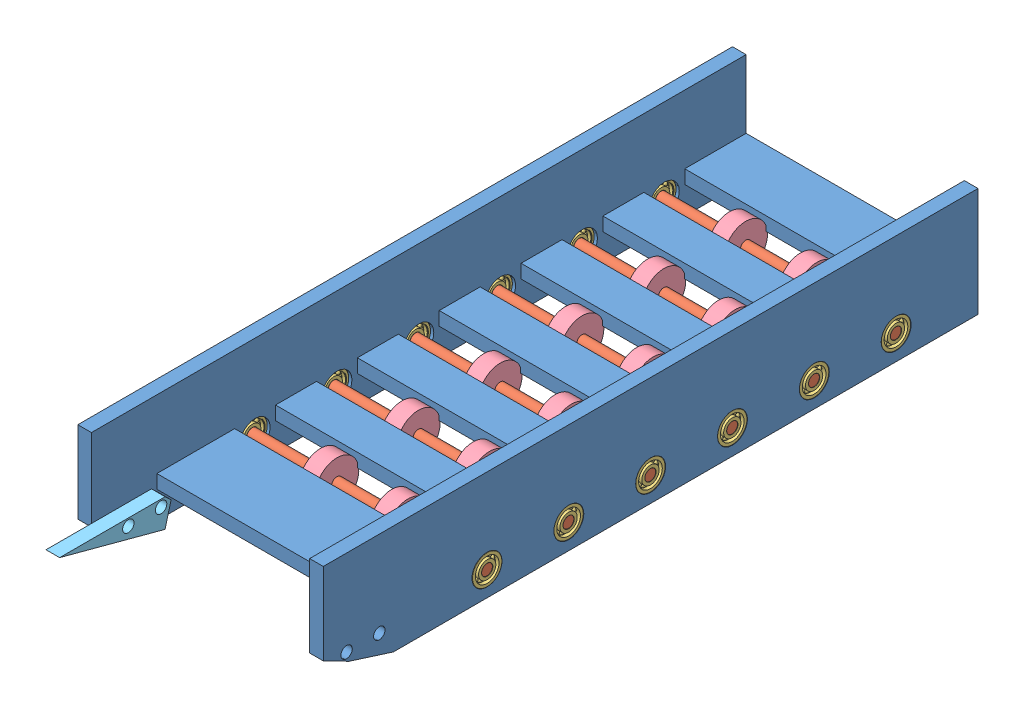
SolidWorks assembly chute_assemble_20241127, configuration 默认. Lengths in mm.
Overall size (90.23 42.03 256.65).
32 component instances, 5 part files, 64 mates.
Components (placement in the parent):
- chute_metal_20241127-1: chute_metal_20241127 [默认] at (2.4605 -4.6428 75) size (90 40 240)
- chute_stick_metal_20241127-1: chute_stick_metal_20241127 [默认] at (47.3105 -10.6428 135) x (0 0 1) z (-1 0 0) size (4 4 90)
- Rolling bearings S719-4 GB 292-94-1: Rolling bearings S719-4 GB 292-94 [Rolling bearings S719-4 GB 292-94] at (-40.6895 -10.6428 135) x (1 0 0) z (0 0.999705 0.024301) size (4 11 11)
- Rolling bearings S719-4 GB 292-94-2: Rolling bearings S719-4 GB 292-94 [Rolling bearings S719-4 GB 292-94] at (45.3905 -10.6428 135) x (-1 0 0) z (0 0.977196 -0.212337) size (4 11 11)
- chute_stickball_metal_20241127-1: chute_stickball_metal_20241127 [默认] at (18.3905 -10.6428 135) x (0 0.978422 0.206615) z (-1 0 0) size (16 16 6)
- chute_stickball_metal_20241127-2: chute_stickball_metal_20241127 [默认] at (-7.6895 -10.6428 135) x (0 -0.199483 0.979901) z (-1 0 0) size (16 16 6)
- Rolling bearings S719-4 GB 292-94-3: Rolling bearings S719-4 GB 292-94 [Rolling bearings S719-4 GB 292-94] at (45.3905 -10.6428 165) x (-1 0 0) z (0 0.977196 -0.212337) size (4 11 11)
- chute_stickball_metal_20241127-3: chute_stickball_metal_20241127 [默认] at (-7.6895 -10.6428 165) x (0 -0.199483 0.979901) z (-1 0 0) size (16 16 6)
- chute_stickball_metal_20241127-4: chute_stickball_metal_20241127 [默认] at (18.3905 -10.6428 165) x (0 0 1) z (-1 0 0) size (16 16 6)
- Rolling bearings S719-4 GB 292-94-4: Rolling bearings S719-4 GB 292-94 [Rolling bearings S719-4 GB 292-94] at (-40.6895 -10.6428 165) x (1 0 0) z (0 0.999705 0.024301) size (4 11 11)
- chute_stick_metal_20241127-2: chute_stick_metal_20241127 [默认] at (47.3105 -10.6428 165) x (0 0 1) z (-1 0 0) size (4 4 90)
- Rolling bearings S719-4 GB 292-94-5: Rolling bearings S719-4 GB 292-94 [Rolling bearings S719-4 GB 292-94] at (45.3905 -10.6428 105) x (-1 0 0) z (0 0.977196 -0.212337) size (4 11 11)
- chute_stickball_metal_20241127-5: chute_stickball_metal_20241127 [默认] at (-7.6895 -10.6428 105) x (0 -0.199483 0.979901) z (-1 0 0) size (16 16 6)
- chute_stickball_metal_20241127-6: chute_stickball_metal_20241127 [默认] at (18.3905 -10.6428 105) x (0 0 1) z (-1 0 0) size (16 16 6)
- Rolling bearings S719-4 GB 292-94-6: Rolling bearings S719-4 GB 292-94 [Rolling bearings S719-4 GB 292-94] at (-40.6895 -10.6428 105) x (1 0 0) z (0 0.999705 0.024301) size (4 11 11)
- chute_stick_metal_20241127-3: chute_stick_metal_20241127 [默认] at (47.3105 -10.6428 105) x (0 0 1) z (-1 0 0) size (4 4 90)
- Rolling bearings S719-4 GB 292-94-7: Rolling bearings S719-4 GB 292-94 [Rolling bearings S719-4 GB 292-94] at (45.3905 -10.6428 195) x (-1 0 0) z (0 0.977196 -0.212337) size (4 11 11)
- chute_stickball_metal_20241127-7: chute_stickball_metal_20241127 [默认] at (-7.6895 -10.6428 195) x (0 -0.199483 0.979901) z (-1 0 0) size (16 16 6)
- chute_stickball_metal_20241127-8: chute_stickball_metal_20241127 [默认] at (18.3905 -10.6428 195) x (0 0.504953 0.863147) z (-1 0 0) size (16 16 6)
- Rolling bearings S719-4 GB 292-94-8: Rolling bearings S719-4 GB 292-94 [Rolling bearings S719-4 GB 292-94] at (-40.6895 -10.6428 195) x (1 0 0) z (0 0.999705 0.024301) size (4 11 11)
- chute_stick_metal_20241127-4: chute_stick_metal_20241127 [默认] at (47.3105 -10.6428 195) x (0 0 1) z (-1 0 0) size (4 4 90)
- chute_stickball_metal_20241127-9: chute_stickball_metal_20241127 [默认] at (-7.6895 -10.6428 225) x (0 -0.092424 0.99572) z (-1 0 0) size (16 16 6)
- chute_stickball_metal_20241127-10: chute_stickball_metal_20241127 [默认] at (18.3905 -10.6428 225) x (0 -0.53296 -0.84614) z (-1 0 0) size (16 16 6)
- Rolling bearings S719-4 GB 292-94-9: Rolling bearings S719-4 GB 292-94 [Rolling bearings S719-4 GB 292-94] at (45.3905 -10.6428 225) x (-1 0 0) z (0 0.977196 -0.212337) size (4 11 11)
- Rolling bearings S719-4 GB 292-94-10: Rolling bearings S719-4 GB 292-94 [Rolling bearings S719-4 GB 292-94] at (-40.6895 -10.6428 225) x (1 0 0) z (0 0.999705 0.024301) size (4 11 11)
- chute_stick_metal_20241127-5: chute_stick_metal_20241127 [默认] at (47.3105 -10.6428 225) x (0 0 1) z (-1 0 0) size (4 4 90)
- Rolling bearings S719-4 GB 292-94-13: Rolling bearings S719-4 GB 292-94 [Rolling bearings S719-4 GB 292-94] at (45.5405 -10.6428 255) x (-1 0 0) z (0 0.977196 -0.212337) size (4 11 11)
- chute_stickball_metal_20241127-13: chute_stickball_metal_20241127 [默认] at (-7.5395 -10.6428 255) x (0 -0.199483 0.979901) z (-1 0 0) size (16 16 6)
- chute_stick_metal_20241127-7: chute_stick_metal_20241127 [默认] at (47.4605 -10.6428 255) x (0 0 1) z (-1 0 0) size (4 4 90)
- Rolling bearings S719-4 GB 292-94-14: Rolling bearings S719-4 GB 292-94 [Rolling bearings S719-4 GB 292-94] at (-40.5395 -10.6428 255) x (1 0 0) z (0 0.999705 0.024301) size (4 11 11)
- chute_stickball_metal_20241127-14: chute_stickball_metal_20241127 [默认] at (18.5405 -10.6428 255) x (0 -0.53296 -0.84614) z (-1 0 0) size (16 16 6)
- chute_intaker_connect_3d_20241128-2: chute_intaker_connect_3d_20241128 [默认] at (-32.5395 -18.8708 293.0176) x (0 0.258819 0.965926) z (-1 0 0) size (40 10.01 5)
Mates (geometry in assembly coordinates):
- 重合1: coincident anti-aligned: circle of chute_stick_metal_20241127-1; circle of Rolling bearings S719-4 GB 292-94-2
- 同心1: concentric anti-aligned: cylinder of chute_stick_metal_20241127-1 through (-42.6895 -10.6428 135) axis (1 0 0) radius 2; cylinder of Rolling bearings S719-4 GB 292-94-1 through (-43.6818 -10.6428 135) axis (-1 0 0) radius 2
- 重合2: coincident aligned: plane of chute_stick_metal_20241127-1 through (-42.6895 -10.6428 135) normal (-1 0 0); plane of Rolling bearings S719-4 GB 292-94-1 through (-42.6895 -10.5942 133.0006) normal (-1 0 0)
- 同心2: concentric aligned: cylinder of chute_stick_metal_20241127-1 through (-42.6895 -10.6428 135) axis (1 0 0) radius 2; cylinder of chute_stickball_metal_20241127-1 through (12.3905 -10.6428 135) axis (1 0 0) radius 2
- 同心3: concentric aligned: cylinder of chute_stick_metal_20241127-1 through (-42.6895 -10.6428 135) axis (1 0 0) radius 2; cylinder of chute_stickball_metal_20241127-2 through (-13.6895 -10.6428 135) axis (1 0 0) radius 2
- 距离1: distance = 25 mm anti-aligned: plane of Rolling bearings S719-4 GB 292-94-2 through (43.3905 -9.9704 138.0945) normal (-1 0 0); plane of chute_stickball_metal_20241127-1 through (18.3905 -10.6428 135) normal (1 0 0)
- 距离2: distance = 25 mm anti-aligned: plane of Rolling bearings S719-4 GB 292-94-1 through (-38.6895 -10.5659 131.8343) normal (1 0 0); plane of chute_stickball_metal_20241127-2 through (-13.6895 -10.6428 135) normal (-1 0 0)
- 距离3: distance = 25 mm anti-aligned: plane of Rolling bearings S719-4 GB 292-94-4 through (-38.6895 -10.5659 161.8343) normal (1 0 0); plane of chute_stickball_metal_20241127-3 through (-13.6895 -10.6428 165) normal (-1 0 0)
- 同心4: concentric anti-aligned: cylinder of Rolling bearings S719-4 GB 292-94-4 through (-43.6818 -10.6428 165) axis (-1 0 0) radius 2; cylinder of chute_stick_metal_20241127-2 through (-42.6895 -10.6428 165) axis (1 0 0) radius 2
- 同心5: concentric aligned: cylinder of chute_stickball_metal_20241127-4 through (12.3905 -10.6428 165) axis (1 0 0) radius 2; cylinder of chute_stick_metal_20241127-2 through (-42.6895 -10.6428 165) axis (1 0 0) radius 2
- 同心6: concentric aligned: cylinder of chute_stickball_metal_20241127-3 through (-13.6895 -10.6428 165) axis (1 0 0) radius 2; cylinder of chute_stick_metal_20241127-2 through (-42.6895 -10.6428 165) axis (1 0 0) radius 2
- 距离4: distance = 25 mm anti-aligned: plane of Rolling bearings S719-4 GB 292-94-3 through (43.3905 -9.9704 168.0945) normal (-1 0 0); plane of chute_stickball_metal_20241127-4 through (18.3905 -10.6428 165) normal (1 0 0)
- 重合5: coincident anti-aligned: circle of Rolling bearings S719-4 GB 292-94-3; circle of chute_stick_metal_20241127-2
- 重合6: coincident aligned: plane of Rolling bearings S719-4 GB 292-94-4 through (-42.6895 -10.5942 163.0006) normal (-1 0 0); plane of chute_stick_metal_20241127-2 through (-42.6895 -10.6428 165) normal (-1 0 0)
- 距离5: distance = 25 mm anti-aligned: plane of Rolling bearings S719-4 GB 292-94-6 through (-38.6895 -10.5659 101.8343) normal (1 0 0); plane of chute_stickball_metal_20241127-5 through (-13.6895 -10.6428 105) normal (-1 0 0)
- 同心7: concentric anti-aligned: cylinder of Rolling bearings S719-4 GB 292-94-6 through (-43.6818 -10.6428 105) axis (-1 0 0) radius 2; cylinder of chute_stick_metal_20241127-3 through (-42.6895 -10.6428 105) axis (1 0 0) radius 2
- 同心8: concentric aligned: cylinder of chute_stickball_metal_20241127-6 through (12.3905 -10.6428 105) axis (1 0 0) radius 2; cylinder of chute_stick_metal_20241127-3 through (-42.6895 -10.6428 105) axis (1 0 0) radius 2
- 同心9: concentric aligned: cylinder of chute_stickball_metal_20241127-5 through (-13.6895 -10.6428 105) axis (1 0 0) radius 2; cylinder of chute_stick_metal_20241127-3 through (-42.6895 -10.6428 105) axis (1 0 0) radius 2
- 距离6: distance = 25 mm anti-aligned: plane of Rolling bearings S719-4 GB 292-94-5 through (43.3905 -9.9704 108.0945) normal (-1 0 0); plane of chute_stickball_metal_20241127-6 through (18.3905 -10.6428 105) normal (1 0 0)
- 重合7: coincident anti-aligned: circle of Rolling bearings S719-4 GB 292-94-5; circle of chute_stick_metal_20241127-3
- 重合8: coincident aligned: plane of Rolling bearings S719-4 GB 292-94-6 through (-42.6895 -10.5942 103.0006) normal (-1 0 0); plane of chute_stick_metal_20241127-3 through (-42.6895 -10.6428 105) normal (-1 0 0)
- 距离7: distance = 25 mm anti-aligned: plane of Rolling bearings S719-4 GB 292-94-8 through (-38.6895 -10.5659 191.8343) normal (1 0 0); plane of chute_stickball_metal_20241127-7 through (-13.6895 -10.6428 195) normal (-1 0 0)
- 同心10: concentric anti-aligned: cylinder of Rolling bearings S719-4 GB 292-94-8 through (-43.6818 -10.6428 195) axis (-1 0 0) radius 2; cylinder of chute_stick_metal_20241127-4 through (-42.6895 -10.6428 195) axis (1 0 0) radius 2
- 同心11: concentric aligned: cylinder of chute_stickball_metal_20241127-8 through (12.3905 -10.6428 195) axis (1 0 0) radius 2; cylinder of chute_stick_metal_20241127-4 through (-42.6895 -10.6428 195) axis (1 0 0) radius 2
- 同心12: concentric aligned: cylinder of chute_stickball_metal_20241127-7 through (-13.6895 -10.6428 195) axis (1 0 0) radius 2; cylinder of chute_stick_metal_20241127-4 through (-42.6895 -10.6428 195) axis (1 0 0) radius 2
- 距离8: distance = 25 mm anti-aligned: plane of Rolling bearings S719-4 GB 292-94-7 through (43.3905 -9.9704 198.0945) normal (-1 0 0); plane of chute_stickball_metal_20241127-8 through (18.3905 -10.6428 195) normal (1 0 0)
- 重合9: coincident anti-aligned: circle of Rolling bearings S719-4 GB 292-94-7; circle of chute_stick_metal_20241127-4
- 重合10: coincident aligned: plane of Rolling bearings S719-4 GB 292-94-8 through (-42.6895 -10.5942 193.0006) normal (-1 0 0); plane of chute_stick_metal_20241127-4 through (-42.6895 -10.6428 195) normal (-1 0 0)
- 重合20: coincident anti-aligned: circle of chute_metal_20241127-1; circle of Rolling bearings S719-4 GB 292-94-6
- 重合21: coincident anti-aligned: circle of chute_metal_20241127-1; circle of Rolling bearings S719-4 GB 292-94-1
- 重合22: coincident anti-aligned: circle of chute_metal_20241127-1; circle of Rolling bearings S719-4 GB 292-94-4
- 重合23: coincident anti-aligned: circle of chute_metal_20241127-1; circle of Rolling bearings S719-4 GB 292-94-8
- 距离9: distance = 25 mm anti-aligned: plane of Rolling bearings S719-4 GB 292-94-10 through (-38.6895 -10.5659 221.8343) normal (1 0 0); plane of chute_stickball_metal_20241127-9 through (-13.6895 -10.6428 225) normal (-1 0 0)
- 同心19: concentric anti-aligned: cylinder of Rolling bearings S719-4 GB 292-94-10 through (-43.6818 -10.6428 225) axis (-1 0 0) radius 2; cylinder of chute_stick_metal_20241127-5 through (-42.6895 -10.6428 225) axis (1 0 0) radius 2
- 同心20: concentric aligned: cylinder of chute_stickball_metal_20241127-10 through (12.3905 -10.6428 225) axis (1 0 0) radius 2; cylinder of chute_stick_metal_20241127-5 through (-42.6895 -10.6428 225) axis (1 0 0) radius 2
- 同心21: concentric aligned: cylinder of chute_stickball_metal_20241127-9 through (-13.6895 -10.6428 225) axis (1 0 0) radius 2; cylinder of chute_stick_metal_20241127-5 through (-42.6895 -10.6428 225) axis (1 0 0) radius 2
- 距离10: distance = 25 mm anti-aligned: plane of Rolling bearings S719-4 GB 292-94-9 through (43.3905 -9.9704 228.0945) normal (-1 0 0); plane of chute_stickball_metal_20241127-10 through (18.3905 -10.6428 225) normal (1 0 0)
- 重合24: coincident anti-aligned: circle of Rolling bearings S719-4 GB 292-94-9; circle of chute_stick_metal_20241127-5
- 重合25: coincident aligned: plane of Rolling bearings S719-4 GB 292-94-10 through (-42.6895 -10.5942 223.0006) normal (-1 0 0); plane of chute_stick_metal_20241127-5 through (-42.6895 -10.6428 225) normal (-1 0 0)
- 重合26: coincident anti-aligned: circle of Rolling bearings S719-4 GB 292-94-11; circle of chute_stick_metal_20241127-6
- 重合27: coincident aligned: plane of chute_stick_metal_20241127-6 through (-42.5395 -10.6428 285) normal (-1 0 0); plane of Rolling bearings S719-4 GB 292-94-12 through (-42.5395 -10.5942 283.0006) normal (-1 0 0)
- 同心22: concentric anti-aligned: cylinder of chute_stick_metal_20241127-6 through (-42.5395 -10.6428 285) axis (1 0 0) radius 2; cylinder of Rolling bearings S719-4 GB 292-94-12 through (-43.5318 -10.6428 285) axis (-1 0 0) radius 2
- 同心23: concentric aligned: cylinder of chute_stick_metal_20241127-6 through (-42.5395 -10.6428 285) axis (1 0 0) radius 2; cylinder of chute_stickball_metal_20241127-12 through (12.5405 -10.6428 285) axis (1 0 0) radius 2
- 距离11: distance = 25 mm anti-aligned: plane of Rolling bearings S719-4 GB 292-94-11 through (43.5405 -9.9704 288.0945) normal (-1 0 0); plane of chute_stickball_metal_20241127-12 through (18.5405 -10.6428 285) normal (1 0 0)
- 同心24: concentric aligned: cylinder of chute_stickball_metal_20241127-11 through (-13.5395 -10.6428 285) axis (1 0 0) radius 2; cylinder of chute_stick_metal_20241127-6 through (-42.5395 -10.6428 285) axis (1 0 0) radius 2
- 距离12: distance = 25 mm anti-aligned: plane of Rolling bearings S719-4 GB 292-94-12 through (-38.5395 -10.5659 281.8343) normal (1 0 0); plane of chute_stickball_metal_20241127-11 through (-13.5395 -10.6428 285) normal (-1 0 0)
- 重合28: coincident anti-aligned: circle of Rolling bearings S719-4 GB 292-94-13; circle of chute_stick_metal_20241127-7
- 重合29: coincident aligned: plane of chute_stick_metal_20241127-7 through (-42.5395 -10.6428 255) normal (-1 0 0); plane of Rolling bearings S719-4 GB 292-94-14 through (-42.5395 -10.5942 253.0006) normal (-1 0 0)
- 同心25: concentric anti-aligned: cylinder of chute_stick_metal_20241127-7 through (-42.5395 -10.6428 255) axis (1 0 0) radius 2; cylinder of Rolling bearings S719-4 GB 292-94-14 through (-43.5318 -10.6428 255) axis (-1 0 0) radius 2
- 同心26: concentric aligned: cylinder of chute_stick_metal_20241127-7 through (-42.5395 -10.6428 255) axis (1 0 0) radius 2; cylinder of chute_stickball_metal_20241127-14 through (12.5405 -10.6428 255) axis (1 0 0) radius 2
- 距离13: distance = 25 mm anti-aligned: plane of Rolling bearings S719-4 GB 292-94-13 through (43.5405 -9.9704 258.0945) normal (-1 0 0); plane of chute_stickball_metal_20241127-14 through (18.5405 -10.6428 255) normal (1 0 0)
- 同心27: concentric aligned: cylinder of chute_stickball_metal_20241127-13 through (-13.5395 -10.6428 255) axis (1 0 0) radius 2; cylinder of chute_stick_metal_20241127-7 through (-42.5395 -10.6428 255) axis (1 0 0) radius 2
- 距离14: distance = 25 mm anti-aligned: plane of Rolling bearings S719-4 GB 292-94-14 through (-38.5395 -10.5659 251.8343) normal (1 0 0); plane of chute_stickball_metal_20241127-13 through (-13.5395 -10.6428 255) normal (-1 0 0)
- 重合30: coincident aligned: circle of chute_metal_20241127-1; circle of Rolling bearings S719-4 GB 292-94-10
- 平行2: parallel aligned: plane of chute_metal_20241127-1 through (-42.5395 -4.6428 315) normal (-1 0 0); plane of chute_stick_metal_20241127-5 through (-42.6895 -10.6428 225) normal (-1 0 0)
- 同心28: concentric anti-aligned: circle of chute_metal_20241127-1; circle of Rolling bearings S719-4 GB 292-94-14
- 重合32: coincident aligned: plane of chute_metal_20241127-1 through (-42.5395 -4.6428 315) normal (-1 0 0); plane of chute_stick_metal_20241127-7 through (-42.5395 -10.6428 255) normal (-1 0 0)
- 同心29: concentric anti-aligned: circle of chute_metal_20241127-1; circle of Rolling bearings S719-4 GB 292-94-12
- 重合33: coincident aligned: plane of chute_metal_20241127-1 through (-42.5395 -4.6428 315) normal (-1 0 0); circle of chute_stick_metal_20241127-6
- 重合49: coincident aligned: circle of chute_metal_20241127-1; circle of chute_intaker_connect_3d_20241128-1
- 同心34: concentric anti-aligned: cylinder of chute_metal_20241127-1 through (-47.5395 -11.1073 306.4645) axis (1 0 0) radius 2.1; cylinder of chute_intaker_connect_3d_20241128-1 through (42.4605 -4.4693 299.8264) axis (-1 0 0) radius 2.1
- 重合50: coincident anti-aligned: cylinder of chute_metal_20241127-1 through (-47.5395 -11.1073 294.4645) axis (1 0 0) radius 2.1; circle of chute_intaker_connect_3d_20241128-2
- 同心35: concentric aligned: cylinder of chute_metal_20241127-1 through (-47.5395 -11.1073 306.4645) axis (1 0 0) radius 2.1; cylinder of chute_intaker_connect_3d_20241128-2 through (-37.5395 -11.1073 306.4645) axis (1 0 0) radius 2.1
- 重合51: coincident anti-aligned: plane of chute_metal_20241127-1 through (-37.5395 -4.6428 315) normal (1 0 0); plane of chute_intaker_connect_3d_20241128-2 through (-37.5395 -18.8708 293.0176) normal (-1 0 0)
